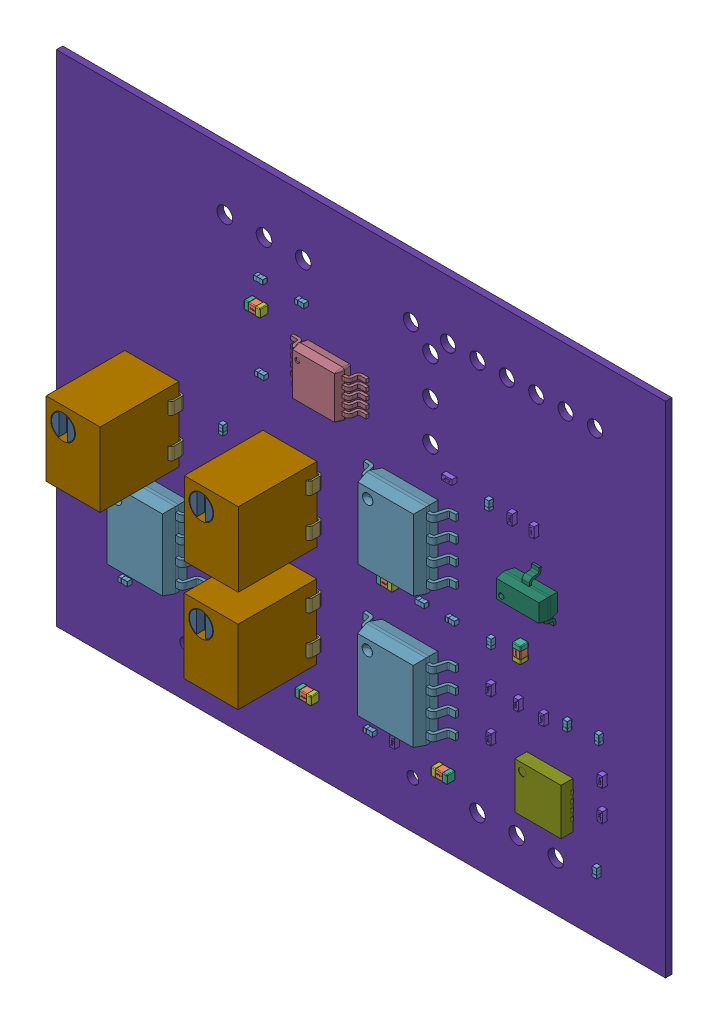
SolidWorks assembly Self_Sensing_Board_V1, configuration Default. Lengths in mm.
Overall size (39.5 32.38 5.69).
118 component instances, 17 part files, 0 mates.
Components (placement in the parent):
- Self_Sensing_Board_V1.step-1: Self_Sensing_Board_V1.step [Default] at origin size (39.5 32.38 5.69)
  - C1.step-1: C1.step [Default] at origin size (0.6 0.3 0.3)
    - Capacitor_0201.step-1: Capacitor_0201.step [Default] at (-26.1191 26.2889 0) x (-1 0 0) z (0 0 1) size (0.6 0.3 0.3)
  - C2.step-1: C2.step [Default] at origin size (0.6 0.3 0.3)
    - Capacitor_0201.step-1: Capacitor_0201.step [Default] at (-23.452 26.2889 0) x (-1 0 0) z (0 0 1) size (0.6 0.3 0.3)
  - C3.step-1: C3.step [Default] at origin size (1.05 0.55 0.55)
    - Capacitor_0402.step-1: Capacitor_0402.step [Default] at (-122.5054 -19.3126 -10.6426) x (-1 0 0) z (0 1 0) size (0.85 0.53 0.53)
    - Capacitor_0402-0.step-1: Capacitor_0402-0.step [Default] at (-122.5054 -19.3126 -10.6426) x (-1 0 0) z (0 1 0) size (0.13 0 0.07)
    - Capacitor_0402-1.step-1: Capacitor_0402-1.step [Default] at (-122.5054 -19.3126 -10.6426) x (-1 0 0) z (0 1 0) size (0.16 0 0.07)
    - Capacitor_0402-2.step-1: Capacitor_0402-2.step [Default] at (-122.5054 -19.3126 -10.6426) x (-1 0 0) z (0 1 0) size (0.08 0 0.07)
    - Capacitor_0402-3.step-1: Capacitor_0402-3.step [Default] at (-122.5054 -19.3126 -10.6426) x (-1 0 0) z (0 1 0) size (0.3 0.55 0.55)
    - Capacitor_0402-4.step-1: Capacitor_0402-4.step [Default] at (-122.5054 -19.3126 -10.6426) x (-1 0 0) z (0 1 0) size (0.3 0.55 0.55)
  - C4.step-1: C4.step [Default] at origin size (0.6 0.3 0.3)
    - Capacitor_0201.step-1: Capacitor_0201.step [Default] at (-26.0441 20.9549 0) x (-1 0 0) z (0 0 1) size (0.6 0.3 0.3)
  - C5.step-1: C5.step [Default] at origin size (1.05 0.55 0.55)
    - Capacitor_0402.step-1: Capacitor_0402.step [Default] at (82.0874 48.5734 -10.6426) x (1 0 0) z (0 -1 0) size (0.85 0.53 0.53)
    - Capacitor_0402-0.step-1: Capacitor_0402-0.step [Default] at (82.0874 48.5734 -10.6426) x (1 0 0) z (0 -1 0) size (0.13 0 0.07)
    - Capacitor_0402-1.step-1: Capacitor_0402-1.step [Default] at (82.0874 48.5734 -10.6426) x (1 0 0) z (0 -1 0) size (0.16 0 0.07)
    - Capacitor_0402-2.step-1: Capacitor_0402-2.step [Default] at (82.0874 48.5734 -10.6426) x (1 0 0) z (0 -1 0) size (0.08 0 0.07)
    - Capacitor_0402-3.step-1: Capacitor_0402-3.step [Default] at (82.0874 48.5734 -10.6426) x (1 0 0) z (0 -1 0) size (0.3 0.55 0.55)
    - Capacitor_0402-4.step-1: Capacitor_0402-4.step [Default] at (82.0874 48.5734 -10.6426) x (1 0 0) z (0 -1 0) size (0.3 0.55 0.55)
  - C6.step-1: C6.step [Default] at origin size (0.3 0.6 0.3)
    - Capacitor_0201.step-1: Capacitor_0201.step [Default] at (-11.3031 21.0561 0) x (0 1 0) z (0 0 1) size (0.6 0.3 0.3)
  - C7.step-1: C7.step [Default] at origin size (0.3 0.6 0.3)
    - Capacitor_0201.step-1: Capacitor_0201.step [Default] at (-28.5579 16.6629 0) x (0 -1 0) z (0 0 1) size (0.6 0.3 0.3)
  - C8.step-1: C8.step [Default] at origin size (0.6 0.3 0.3)
    - Capacitor_0201.step-1: Capacitor_0201.step [Default] at (-15.6469 13.3351 0) x (1 0 0) z (0 0 1) size (0.6 0.3 0.3)
  - C9.step-1: C9.step [Default] at origin size (0.6 0.3 0.3)
    - Capacitor_0201.step-1: Capacitor_0201.step [Default] at (-34.8989 4.9531 0) x (1 0 0) z (0 0 1) size (0.6 0.3 0.3)
  - C11.step-1: C11.step [Default] at origin size (0.3 0.6 0.3)
    - Capacitor_0201.step-1: Capacitor_0201.step [Default] at (-11.1591 13.3611 0) x (0 1 0) z (0 0 1) size (0.6 0.3 0.3)
  - C14.step-1: C14.step [Default] at origin size (0.3 0.6 0.3)
    - Capacitor_0201.step-1: Capacitor_0201.step [Default] at (-6.2231 11.2021 0) x (0 1 0) z (0 0 1) size (0.6 0.3 0.3)
  - R1.step-1: R1.step [Default] at origin size (0.68 0.33 0.34)
    - Resistor_0201.step-1: Resistor_0201.step [Default] at (-13.8691 21.2089 0) x (-1 0 0) z (0 1 0) size (0.68 0.34 0.33)
  - R2.step-1: R2.step [Default] at origin size (3.9 4.8 5.3)
    - SM-42TW.step-1: SM-42TW.step [Default] at (-33.1301 15.4941 5.2832) x (-1 0 0) z (0 0 1) size (3.9 4.8 5.3)
      - _SM-42W.step-1: _SM-42W.step [Default] x (0 1 0) z (1 0 0) size (4.8 5.1 3.5)
      - _SM-42-dial.step-1: _SM-42-dial.step [Default] at (0.65 -1.2 0) x (-1 0 0) z (0 1 0) size (1.5 0.7 1.5)
      - _SM-42W_terminal.step-1: _SM-42W_terminal.step [Default] at (0.95 0 -4.46) x (0 1 0) z (1 0 0) size (1.3 0.9 1)
      - _SM-42W_terminal-2.step-1: _SM-42W_terminal-2.step [Default] at (-0.95 -1.27 -4.46) x (0 -1 0) z (-1 0 0) size (0.8 0.9 1)
      - _SM-42W_terminal-2.step-2: _SM-42W_terminal-2.step [Default] at (-0.95 1.27 -4.46) x (0 -1 0) z (-1 0 0) size (0.8 0.9 1)
  - R3.step-1: R3.step [Default] at origin size (3.9 4.8 5.3)
    - SM-42TW.step-1: SM-42TW.step [Default] at (-24.1681 15.4941 5.2832) x (-1 0 0) z (0 0 1) size (3.9 4.8 5.3)
      - _SM-42W.step-1: _SM-42W.step [Default] x (0 1 0) z (1 0 0) size (4.8 5.1 3.5)
      - _SM-42-dial.step-1: _SM-42-dial.step [Default] at (0.65 -1.2 0) x (-1 0 0) z (0 1 0) size (1.5 0.7 1.5)
      - _SM-42W_terminal.step-1: _SM-42W_terminal.step [Default] at (0.95 0 -4.46) x (0 1 0) z (1 0 0) size (1.3 0.9 1)
      - _SM-42W_terminal-2.step-1: _SM-42W_terminal-2.step [Default] at (-0.95 -1.27 -4.46) x (0 -1 0) z (-1 0 0) size (0.8 0.9 1)
      - _SM-42W_terminal-2.step-2: _SM-42W_terminal-2.step [Default] at (-0.95 1.27 -4.46) x (0 -1 0) z (-1 0 0) size (0.8 0.9 1)
  - R4.step-1: R4.step [Default] at origin size (0.33 0.68 0.34)
    - Resistor_0201.step-1: Resistor_0201.step [Default] at (-30.4799 4.9789 0) x (0 -1 0) z (-1 0 0) size (0.68 0.34 0.33)
  - R5.step-1: R5.step [Default] at origin size (0.33 0.68 0.34)
    - Resistor_0201.step-1: Resistor_0201.step [Default] at (-11.1591 10.7691 0) x (0 1 0) z (1 0 0) size (0.68 0.34 0.33)
  - R6.step-1: R6.step [Default] at origin size (0.33 0.68 0.34)
    - Resistor_0201.step-1: Resistor_0201.step [Default] at (-7.7299 10.8209 0) x (0 -1 0) z (-1 0 0) size (0.68 0.34 0.33)
  - R7.step-1: R7.step [Default] at origin size (0.33 0.68 0.34)
    - Resistor_0201.step-1: Resistor_0201.step [Default] at (-11.1591 8.0271 0) x (0 1 0) z (1 0 0) size (0.68 0.34 0.33)
  - R8.step-1: R8.step [Default] at origin size (0.33 0.68 0.34)
    - Resistor_0201.step-1: Resistor_0201.step [Default] at (-3.9371 9.2451 0) x (0 1 0) z (1 0 0) size (0.68 0.34 0.33)
  - R9.step-1: R9.step [Default] at origin size (0.33 0.68 0.34)
    - Resistor_0201.step-1: Resistor_0201.step [Default] at (-9.3811 10.8211 0) x (0 1 0) z (1 0 0) size (0.68 0.34 0.33)
  - R10.step-1: R10.step [Default] at origin size (0.33 0.68 0.34)
    - Resistor_0201.step-1: Resistor_0201.step [Default] at (-3.9371 7.2651 0) x (0 1 0) z (1 0 0) size (0.68 0.34 0.33)
  - R11.step-1: R11.step [Default] at origin size (1.05 0.55 0.55)
    - Capacitor_0402.step-1: Capacitor_0402.step [Default] at (-119.2034 -39.4294 -10.6426) x (-1 0 0) z (0 1 0) size (0.85 0.53 0.53)
    - Capacitor_0402-0.step-1: Capacitor_0402-0.step [Default] at (-119.2034 -39.4294 -10.6426) x (-1 0 0) z (0 1 0) size (0.13 0 0.07)
    - Capacitor_0402-1.step-1: Capacitor_0402-1.step [Default] at (-119.2034 -39.4294 -10.6426) x (-1 0 0) z (0 1 0) size (0.16 0 0.07)
    - Capacitor_0402-2.step-1: Capacitor_0402-2.step [Default] at (-119.2034 -39.4294 -10.6426) x (-1 0 0) z (0 1 0) size (0.08 0 0.07)
    - Capacitor_0402-3.step-1: Capacitor_0402-3.step [Default] at (-119.2034 -39.4294 -10.6426) x (-1 0 0) z (0 1 0) size (0.3 0.55 0.55)
    - Capacitor_0402-4.step-1: Capacitor_0402-4.step [Default] at (-119.2034 -39.4294 -10.6426) x (-1 0 0) z (0 1 0) size (0.3 0.55 0.55)
  - R12.step-1: R12.step [Default] at origin size (3.9 4.8 5.3)
    - SM-42TW.step-1: SM-42TW.step [Default] at (-24.1851 8.8901 5.2832) x (-1 0 0) z (0 0 1) size (3.9 4.8 5.3)
      - _SM-42W.step-1: _SM-42W.step [Default] x (0 1 0) z (1 0 0) size (4.8 5.1 3.5)
      - _SM-42-dial.step-1: _SM-42-dial.step [Default] at (0.65 -1.2 0) x (-1 0 0) z (0 1 0) size (1.5 0.7 1.5)
      - _SM-42W_terminal.step-1: _SM-42W_terminal.step [Default] at (0.95 0 -4.46) x (0 1 0) z (1 0 0) size (1.3 0.9 1)
      - _SM-42W_terminal-2.step-1: _SM-42W_terminal-2.step [Default] at (-0.95 -1.27 -4.46) x (0 -1 0) z (-1 0 0) size (0.8 0.9 1)
      - _SM-42W_terminal-2.step-2: _SM-42W_terminal-2.step [Default] at (-0.95 1.27 -4.46) x (0 -1 0) z (-1 0 0) size (0.8 0.9 1)
  - R13.step-1: R13.step [Default] at origin size (1.05 0.55 0.55)
    - Capacitor_0402.step-1: Capacitor_0402.step [Default] at (-113.9354 -30.4124 -10.6426) x (-1 0 0) z (0 1 0) size (0.85 0.53 0.53)
    - Capacitor_0402-0.step-1: Capacitor_0402-0.step [Default] at (-113.9354 -30.4124 -10.6426) x (-1 0 0) z (0 1 0) size (0.13 0 0.07)
    - Capacitor_0402-1.step-1: Capacitor_0402-1.step [Default] at (-113.9354 -30.4124 -10.6426) x (-1 0 0) z (0 1 0) size (0.16 0 0.07)
    - Capacitor_0402-2.step-1: Capacitor_0402-2.step [Default] at (-113.9354 -30.4124 -10.6426) x (-1 0 0) z (0 1 0) size (0.08 0 0.07)
    - Capacitor_0402-3.step-1: Capacitor_0402-3.step [Default] at (-113.9354 -30.4124 -10.6426) x (-1 0 0) z (0 1 0) size (0.3 0.55 0.55)
    - Capacitor_0402-4.step-1: Capacitor_0402-4.step [Default] at (-113.9354 -30.4124 -10.6426) x (-1 0 0) z (0 1 0) size (0.3 0.55 0.55)
  - R14.step-1: R14.step [Default] at origin size (0.33 0.68 0.34)
    - Resistor_0201.step-1: Resistor_0201.step [Default] at (-8.3651 21.0561 0) x (0 1 0) z (1 0 0) size (0.68 0.34 0.33)
  - R15.step-1: R15.step [Default] at origin size (0.33 0.68 0.34)
    - Resistor_0201.step-1: Resistor_0201.step [Default] at (-9.7789 21.0559 0) x (0 -1 0) z (-1 0 0) size (0.68 0.34 0.33)
  - U1.step-1: U1.step [Default] at origin size (4.9 3 1.15)
    - AD9833BRMZ.step-1: AD9833BRMZ.step [Default] at (-21.6759 22.9871 0) x (1 0 0) z (0 0 1) size (4.9 3 1.15)
  - U2.step-1: U2.step [Default] at origin size (6 4.9 1.75)
    - 8-SOIC.step-1: 8-SOIC.step [Default] at (-16.3913 17.3228 0) x (0 -1 0) z (0 0 1) size (4.9 6 1.75)
  - U3.step-1: U3.step [Default] at origin size (6 4.9 1.75)
    - 8-SOIC.step-1: 8-SOIC.step [Default] at (-32.6727 9.1948 0) x (0 -1 0) z (0 0 1) size (4.9 6 1.75)
  - U5.step-1: U5.step [Default] at origin size (6 4.9 1.75)
    - 8-SOIC.step-1: 8-SOIC.step [Default] at (-16.4167 8.8138 0) x (0 -1 0) z (0 0 1) size (4.9 6 1.75)
  - U6.step-1: U6.step [Default] at origin size (2.9 2.8 1.3)
    - SOT-23-3.step-1: SOT-23-3.step [Default] at (-8.2905 17.6863 0) x (1 0 0) z (0 0 1) size (2.9 2.8 1.3)
  - C10.step-1: C10.step [Default] at origin size (0.3 0.6 0.3)
    - Capacitor_0201.step-1: Capacitor_0201.step [Default] at (-4.1739 11.4559 0) x (0 -1 0) z (0 0 1) size (0.6 0.3 0.3)
  - C12.step-1: C12.step [Default] at origin size (0.6 0.3 0.3)
    - Capacitor_0201.step-1: Capacitor_0201.step [Default] at (-13.6901 13.3349 0) x (-1 0 0) z (0 0 1) size (0.6 0.3 0.3)
  - C13.step-1: C13.step [Default] at origin size (0.3 0.6 0.3)
    - Capacitor_0201.step-1: Capacitor_0201.step [Default] at (-4.3181 3.9111 0) x (0 1 0) z (0 0 1) size (0.6 0.3 0.3)
  - C15.step-1: C15.step [Default] at origin size (0.6 0.3 0.3)
    - Capacitor_0201.step-1: Capacitor_0201.step [Default] at (-19.0069 4.4451 0) x (1 0 0) z (0 0 1) size (0.6 0.3 0.3)
  - U4.step-1: U4.step [Default] at origin size (3.02 3 0.8)
    - 8-LFCSP-WD.step-1: 8-LFCSP-WD.step [Default] at (-7.4761 6.7296 0) x (0 -1 0) z (-1 0 0) size (3 0.8 3.02)
  - C16.step-1: C16.step [Default] at origin size (0.55 1.05 0.55)
    - Capacitor_0402.step-1: Capacitor_0402.step [Default] at (-53.1454 110.1544 -10.6426) x (0 1 0) z (1 0 0) size (0.85 0.53 0.53)
    - Capacitor_0402-0.step-1: Capacitor_0402-0.step [Default] at (-53.1454 110.1544 -10.6426) x (0 1 0) z (1 0 0) size (0.13 0 0.07)
    - Capacitor_0402-1.step-1: Capacitor_0402-1.step [Default] at (-53.1454 110.1544 -10.6426) x (0 1 0) z (1 0 0) size (0.16 0 0.07)
    - Capacitor_0402-2.step-1: Capacitor_0402-2.step [Default] at (-53.1454 110.1544 -10.6426) x (0 1 0) z (1 0 0) size (0.08 0 0.07)
    - Capacitor_0402-3.step-1: Capacitor_0402-3.step [Default] at (-53.1454 110.1544 -10.6426) x (0 1 0) z (1 0 0) size (0.3 0.55 0.55)
    - Capacitor_0402-4.step-1: Capacitor_0402-4.step [Default] at (-53.1454 110.1544 -10.6426) x (0 1 0) z (1 0 0) size (0.3 0.55 0.55)
  - D1.step-1: D1.step [Default] at origin size (0.33 0.68 0.34)
    - Resistor_0201.step-1: Resistor_0201.step [Default] at (-17.3989 4.7249 0) x (0 -1 0) z (-1 0 0) size (0.68 0.34 0.33)
  - Board.step-1: Board.step [Default] at origin size (39.5 32.38 0.41)
